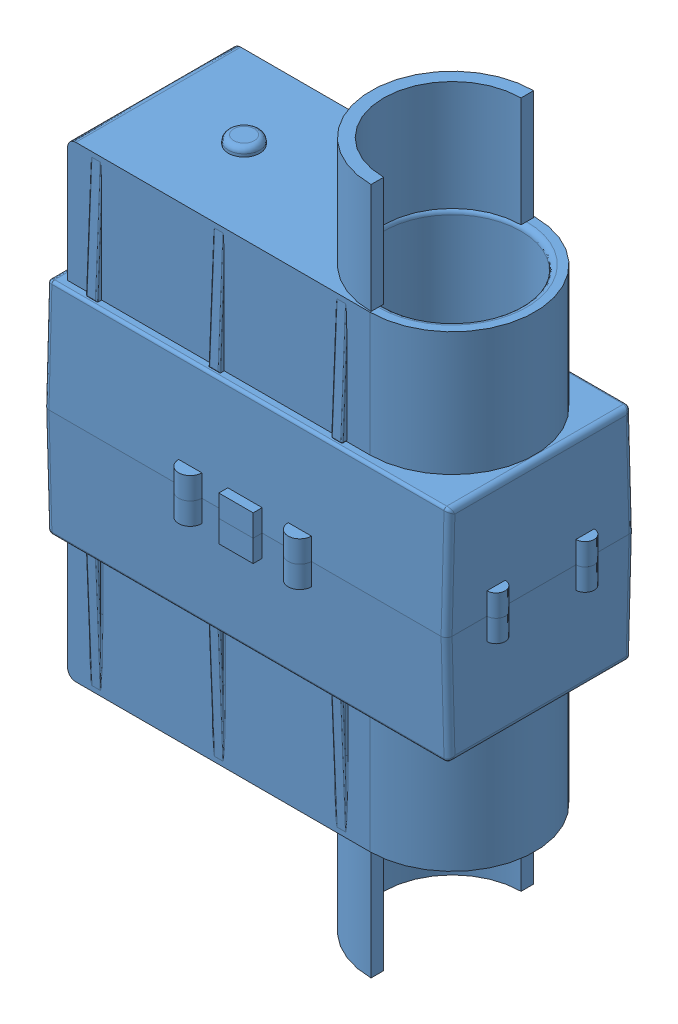
SolidWorks assembly Elevation_Rotator_Unit_Assembly, configuration Default. Lengths in mm.
Overall size (153.3 250 81.22).
3 component instances, 2 part files, 6 mates.
Components (placement in the parent):
- Elevation_Rotator_Unit-1: Elevation_Rotator_Unit [Default] at (91.8654 71.2783 111.7929) size (153.3 125 76.83)
- Elevation_Rotator_Unit-2: Elevation_Rotator_Unit [Default] at (91.8654 -8.7217 111.7929) x (1 0 0) z (0 0 -1) size (153.3 125 76.83)
- Az&El_Connector-1: Az&El_Connector [По умолчанию] at (59.1632 93.3313 81.7929) size (27 27 16.4)
Mates (geometry in assembly coordinates):
- Coincident1: coincident anti-aligned: plane of Elevation_Rotator_Unit-1 through (91.8654 31.2783 111.7929) normal (0 -1 0); plane of Elevation_Rotator_Unit-2 through (91.8654 31.2783 111.7929) normal (0 1 0)
- Coincident2: coincident anti-aligned: line of Elevation_Rotator_Unit-1 through (-22.6944 31.2783 98.9363) axis (0 0 1); line of Elevation_Rotator_Unit-2 through (-22.6944 31.2783 124.6496) axis (0 0 -1)
- Coincident4: coincident anti-aligned: line of Elevation_Rotator_Unit-1 through (-20.6944 31.2783 145.9896) axis (1 0 0); line of Elevation_Rotator_Unit-2 through (121.9587 31.2783 145.9896) axis (-1 0 0)
- Lock1: lock: unknown of Elevation_Rotator_Unit-1; unknown of Elevation_Rotator_Unit-2
- Width1: width aligned: plane of онц-бс-1-19-18-в1-1-в-1 through (45.6632 82.8313 80.3929) normal (-1 0 0); plane of Elevation_Rotator_Unit-1 through (72.6632 82.8313 80.3929) normal (1 0 0); plane of онц-бс-1-19-18-в1-1-в-1 through (79.461 71.2783 80.0234) normal (-1 0 0); plane of Elevation_Rotator_Unit-1 through (38.8654 71.2783 81.7929) normal (1 0 0)
- Lock2: lock: unknown of Elevation_Rotator_Unit-1; unknown of онц-бс-1-19-18-в1-1-в-1
